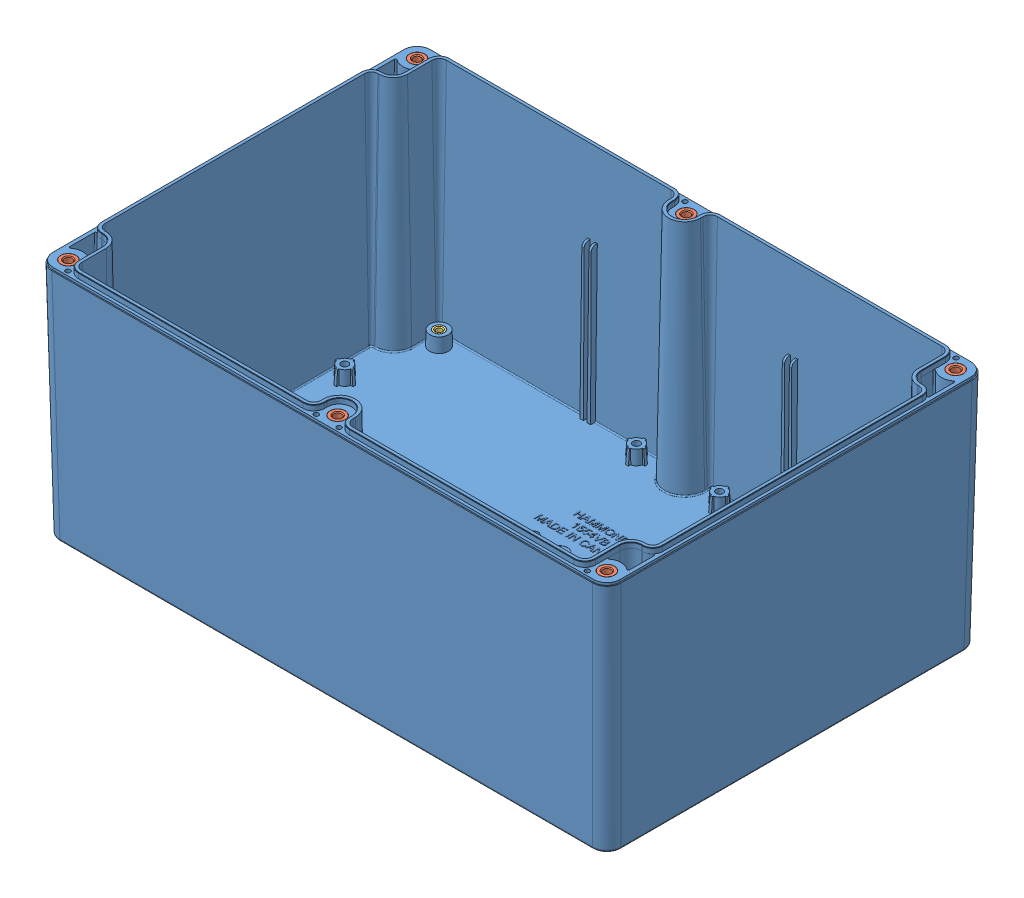
SolidWorks assembly enclosure-bottom, configuration Default. Lengths in mm.
Overall size (239.98 102.76 159.98).
11 component instances, 3 part files, 15 mates.
Components (placement in the parent):
- 1554VB Box-1: 1554VB Box [Default] x (1 0 0) z (0 1 0) size (239.98 159.98 102.76)
- IN-M4 (insert M4-0.7X5.75mm SS)-1: IN-M4 (insert M4-0.7X5.75mm SS) [Default] at (-113.5 -6.35 -73.5) size (6.35 6.35 6.35)
- IN-M4 (insert M4-0.7X5.75mm SS)-2: IN-M4 (insert M4-0.7X5.75mm SS) [Default] at (113.5 -6.35 -73.5) size (6.35 6.35 6.35)
- IN-M4 (insert M4-0.7X5.75mm SS)-3: IN-M4 (insert M4-0.7X5.75mm SS) [Default] at (113.5 -6.35 73.5) size (6.35 6.35 6.35)
- IN-M4 (insert M4-0.7X5.75mm SS)-4: IN-M4 (insert M4-0.7X5.75mm SS) [Default] at (-113.5 -6.35 73.5) size (6.35 6.35 6.35)
- IN-M4 (insert M4-0.7X5.75mm SS)-5: IN-M4 (insert M4-0.7X5.75mm SS) [Default] at (0 -6.35 73.5) size (6.35 6.35 6.35)
- IN-M4 (insert M4-0.7X5.75mm SS)-6: IN-M4 (insert M4-0.7X5.75mm SS) [Default] at (0 -6.35 -73.5) size (6.35 6.35 6.35)
- IN100 (insert M3-0.5X5.75mm BRASS)-1: IN100 (insert M3-0.5X5.75mm BRASS) [Default] at (-100.75 -96.515 70) size (4.83 5.72 4.83)
- IN100 (insert M3-0.5X5.75mm BRASS)-2: IN100 (insert M3-0.5X5.75mm BRASS) [Default] at (-100.75 -96.515 -70) size (4.83 5.72 4.83)
- IN100 (insert M3-0.5X5.75mm BRASS)-3: IN100 (insert M3-0.5X5.75mm BRASS) [Default] at (100.75 -96.515 -70) size (4.83 5.72 4.83)
- IN100 (insert M3-0.5X5.75mm BRASS)-4: IN100 (insert M3-0.5X5.75mm BRASS) [Default] at (100.75 -96.515 70) size (4.83 5.72 4.83)
Mates (geometry in assembly coordinates):
- Coincident2: coincident: plane of ? through (-148.6183 135.0548 -217.0066) normal (0 -1 0); plane of ? through (89.6317 135.0548 -207.1132) normal (0 1 0)
- Concentric1: concentric anti-aligned: cone of ? through (102.7349 126.4839 -55.3632) axis (0 -1 0); cylinder of ? through (102.7349 112.3639 -55.3632) axis (0 1 0) radius 1.74
- Coincident3: coincident anti-aligned: plane of ? through (106.4849 126.4839 -59.1882) normal (0 1 0); plane of ? through (100.5276 126.4839 -59.3659) normal (0 -1 0)
- Coincident4: coincident anti-aligned: plane of ? through (106.4849 126.4839 -59.1882) normal (0 1 0); plane of ? through (99.8129 126.4839 -205.8782) normal (0 -1 0)
- Concentric2: concentric anti-aligned: cone of ? through (102.7349 126.4839 -202.3632) axis (0 -1 0); cylinder of ? through (102.7349 112.3639 -202.3632) axis (0 1 0) radius 1.74
- Coincident5: coincident anti-aligned: plane of ? through (106.4849 126.4839 -59.1882) normal (0 1 0); plane of ? through (-14.3762 126.4839 -205.1656) normal (0 -1 0)
- Concentric3: concentric anti-aligned: cone of ? through (-10.7651 126.4839 -202.3632) axis (0 -1 0); cylinder of ? through (-10.7651 112.3639 -202.3632) axis (0 1 0) radius 1.74
- Coincident6: coincident anti-aligned: plane of ? through (106.4849 126.4839 -59.1882) normal (0 1 0); plane of ? through (-128.4325 126.4839 -204.2409) normal (0 -1 0)
- Concentric4: concentric anti-aligned: cone of ? through (-124.2651 126.4839 -202.3632) axis (0 -1 0); cylinder of ? through (-124.2651 112.3639 -202.3632) axis (0 1 0) radius 1.74
- Coincident7: coincident anti-aligned: plane of ? through (106.4849 126.4839 -59.1882) normal (0 1 0); plane of ? through (-128.7604 126.4839 -56.1915) normal (0 -1 0)
- Concentric5: concentric anti-aligned: cone of ? through (-124.2651 126.4839 -55.3632) axis (0 -1 0); cylinder of ? through (-124.2651 112.3639 -55.3632) axis (0 1 0) radius 1.74
- Coincident8: coincident anti-aligned: plane of ? through (106.4849 126.4839 -59.1882) normal (0 1 0); plane of ? through (-15.3315 126.4839 -55.1607) normal (0 -1 0)
- Concentric6: concentric anti-aligned: cone of ? through (-10.7651 126.4839 -55.3632) axis (0 -1 0); cylinder of ? through (-10.7651 112.3639 -55.3632) axis (0 1 0) radius 1.74
- Width6: width: plane of ? through (91.3817 135.0548 -63.0057) normal (0.999848 0.017452 0); plane of ? through (-148.6183 135.0548 -211.0075) normal (-0.999848 0.017452 0); plane of ? through (90.1317 133.2548 -183.3632) normal (1 0.000001 0); plane of ? through (-147.3683 134.5548 -183.3632) normal (-1 0.000001 0)
- Width7: width anti-aligned: plane of ? through (85.3826 135.0548 -217.0066) normal (0 0.017452 -0.999848); plane of ? through (-142.6192 135.0548 -57.0066) normal (0 0.017452 0.999848); plane of ? through (-133.1183 133.2548 -215.7566) normal (0 0.000001 -1); plane of ? through (-133.1183 134.5548 -58.2566) normal (0 0.000001 1)
